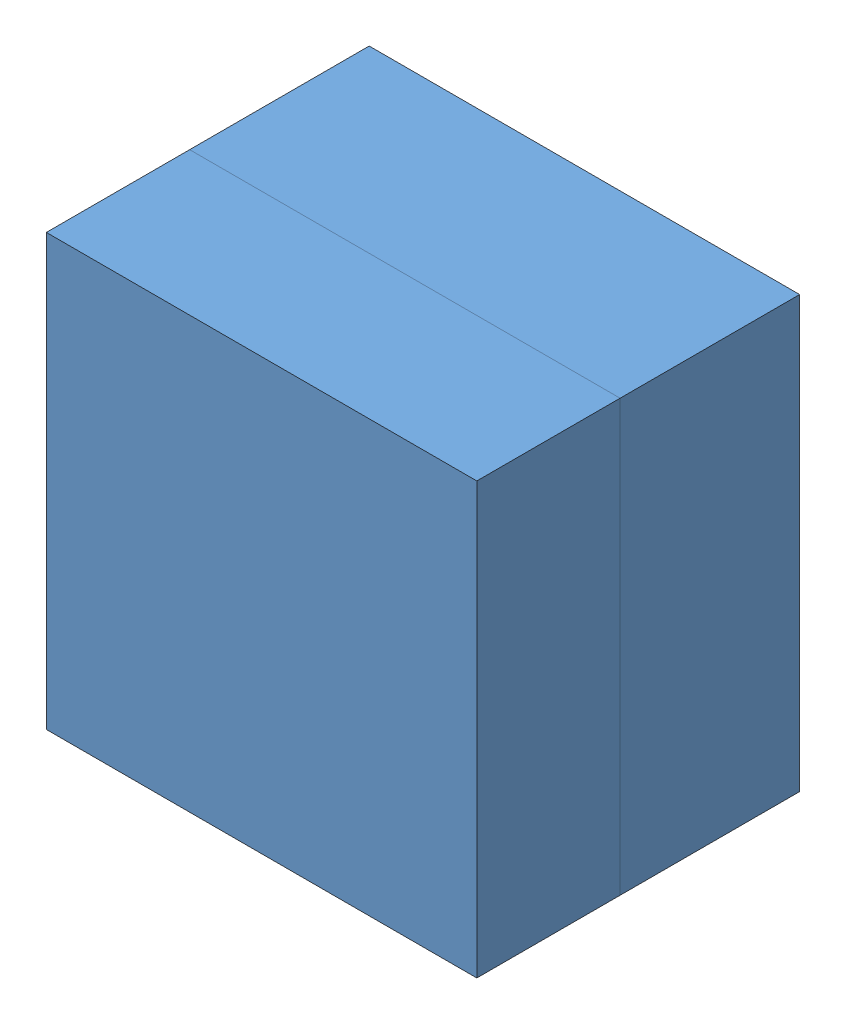
SolidWorks assembly Mold assembly, configuration Default. Lengths in mm.
Overall size (304.8 304.8 228.6).
2 component instances, 2 part files, 0 mates.
Components (placement in the parent):
- MOLD SECTION 1-1: MOLD SECTION 1 [Default] at (-22.6398 -217.3673 261.3665) size (304.8 304.8 228.6)
- CARBON WHEEL (solid for mold) R2.0-1: CARBON WHEEL (solid for mold) R2.0 [Default] at (-21.7311 -217.445 375.4522) x (1 0 0) z (0 -1 0) size (277.11 219.77 277.11)
